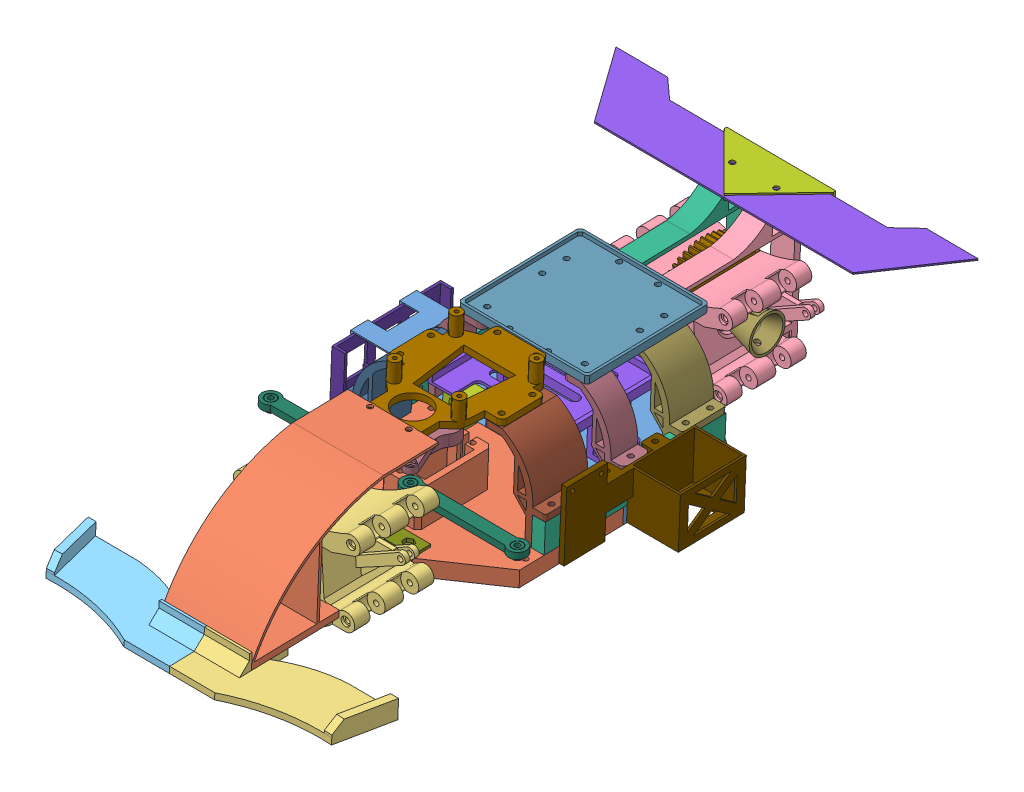
SolidWorks assembly Assem1, configuration Default. Lengths in mm.
Overall size (281.48 111.73 517.58).
43 component instances, 34 part files, 118 mates.
Components (placement in the parent):
- BB_Base-1: BB_Base [Default] at (28.6093 93.0226 121.9081) x (-0.998953 0.035235 0.029162) z (-0.029384 -0.005782 -0.999551) size (160 12.5 120)
- FF_Base-1: FF_Base [Default] at (31.1069 93.5141 206.87) x (0.998953 -0.035235 -0.029162) z (0.029384 0.005782 0.999551) size (160 41.5 120)
- FFDrive_BaseV2-1: FFDrive_BaseV2 [Default] at (33.3841 93.9622 284.3352) x (0.998953 -0.035235 -0.029162) z (0.029384 0.005782 0.999551) size (118.58 68.56 76.42)
- BBDrive_BaseV82-1: BBDrive_BaseV82 [Default] at (24.4221 92.1987 -20.528) x (0.998953 -0.035235 -0.029162) z (0.029384 0.005782 0.999551) size (118.58 68.56 102.04)
- SeizeF-1: SeizeF [Default] at (33.0586 90.9208 276.859) x (-0.998953 0.035235 0.029162) z (-0.029384 -0.005782 -0.999551) size (60 6.8 86)
- Body_sideL-1: Body_sideL [Default] at (-120.6554 114.7973 126.1701) x (-0.998953 0.035235 0.029162) z (0.03505 0.999362 -0.006811) size (10 148 23)
- Body_sideL-2: Body_sideL [Default] at (179.5564 119.2173 117.3192) x (0.998953 -0.035235 -0.029162) z (-0.03505 -0.999362 0.006811) size (10 148 23)
- Pi5_coverF-1: Pi5_coverF [Default] at (31.1961 123.3056 173.9303) x (0.998953 -0.035235 -0.029162) z (0.029384 0.005782 0.999551) size (85 35 25)
- Pi5_coverB-1: Pi5_coverB [Default] at (29.4104 122.9612 114.208) x (0.998953 -0.035235 -0.029162) z (0.029384 0.005782 0.999551) size (95 42 96)
- Lidar-1: Lidar [Default] at (34.5231 195.8195 208.2733) x (-0.029384 -0.005782 -0.999551) z (0.998953 -0.035235 -0.029162) size (114.37 20 89.02)
- LidarArmR-2: LidarArmR [Default] at (-15.6749 -85.014 186.3697) x (0.998559 -0.035298 -0.040412) z (0.040627 0.005385 0.99916) size (48.99 69.85 45)
- LidarArmL-2: LidarArmL [Default] at (64.8691 -87.5454 229.4349) x (-0.998953 0.035235 0.029162) z (-0.029384 -0.005782 -0.999551) size (48.99 69.85 45)
- LidarArmBack-1: LidarArmBack [Default] at (-18.294 -85.6212 83.8021) x (0.998953 -0.035235 -0.029162) z (0.029384 0.005782 0.999551) size (48.99 69.85 36)
- LidarArmBack-2: LidarArmBack [Default] at (61.5781 -88.193 117.4852) x (-0.998953 0.035235 0.029162) z (-0.029384 -0.005782 -0.999551) size (48.99 69.85 36)
- LidarArmMiddle-1: LidarArmMiddle [Default] at (-16.384 -85.2454 148.773) x (0.998953 -0.035235 -0.029162) z (0.029384 0.005782 0.999551) size (48.99 69.85 22)
- LidarArmMiddle-2: LidarArmMiddle [Default] at (62.9003 -87.9328 162.465) x (-0.998953 0.035235 0.029162) z (-0.029384 -0.005782 -0.999551) size (48.99 69.85 22)
- Box-1: Box [Default] at (-11.4334 176.0173 2.6909) x (0.998953 -0.035235 -0.029162) z (0.029384 0.005782 0.999551) size (100 6 100)
- MoterV3-1: MoterV3 [Default] at (-25.1001 106.1781 -59.4629) x (0.998953 -0.035235 -0.029162) z (0.03505 0.999362 -0.006811) size (37.37 43.05 44.5)
- FFBody_to_Drive-1: FFBody_to_Drive [Default] at (-13.9518 104.2128 3.1803) x (0.998953 -0.035235 -0.029162) z (0.029384 0.005782 0.999551) size (60 4 80)
- Battery-1: Battery [Default] at (74.6926 128.1789 305.2934) x (-0.998953 0.035235 0.029162) z (-0.029384 -0.005782 -0.999551) size (44 39 89)
- Radio-2: Radio [Default] at (-13.0755 129.1969 3.01) x (0.998953 -0.035235 -0.029162) z (0.029384 0.005782 0.999551) size (50 55 109.5)
- Battery_Lid-1: Battery_Lid [Default] at (-12.9003 134.1937 2.976) x (0.998953 -0.035235 -0.029162) z (0.029384 0.005782 0.999551) size (46 3 54)
- F1_1-1: F1_1 [Default] at (20.985 -17.6584 2.4568) x (0.998953 -0.035235 -0.029162) z (0.029384 0.005782 0.999551) size (70 82.35 150.07)
- F1_2-2: F1_2 [Default] at (64.4296 96.1923 0.5207) x (0.998953 -0.035235 -0.029162) z (0.029384 0.005782 0.999551) size (120 17.86 60)
- SpoilerTouch2-1: SpoilerTouch2 [Default] at (-4.7419 -16.7482 3.6059) x (0.998956 -0.035234 -0.029079) z (0.0293 0.005785 0.999554) size (18 100.35 111.06)
- F1_2_2-1: F1_2_2 [Default] at (64.4296 96.1923 0.5207) x (0.998953 -0.035235 -0.029162) z (0.029384 0.005782 0.999551) size (120 17.86 60)
- SpoilerTouch-5: SpoilerTouch [Default] at (-38.6157 -15.5519 4.8212) x (0.998773 -0.035267 -0.034779) z (0.034997 0.005584 0.999372) size (18 100.35 111.06)
- SpoilerCover-1: SpoilerCover [Default] at (-10.6832 197.6036 2.515) x (0.998969 -0.035232 -0.028621) z (0.028842 0.005801 0.999567) size (84.34 4.8 47)
- Spoiler-4: Spoiler [Default] at (-10.7673 195.2051 2.5313) x (0.998969 -0.035232 -0.028621) z (0.028842 0.005801 0.999567) size (140 1.2 60)
- Spoiler-5: Spoiler [Default] at (68.019 193.6272 0.2671) x (-0.998969 0.035232 0.028621) z (0.028842 0.005801 0.999567) size (140 1.2 60)
- GearRccar52T.step-1: GearRccar52T.step [Default] at (32.7657 128.7205 11.1737) x (-0.029157 0.000668 -0.999575) z (-0.998953 0.035235 0.029162) size (81 81 12.5)
  - Spur Gear (52 teeth).step-1: Spur Gear (52 teeth).step [Default] at origin size (81 81 12.5)
- Driven_axel-1: Driven_axel [Default] at (20.2788 129.161 11.5382) x (-0.035238 -0.999379 0.000398) z (0.029158 -0.00063 0.999575) size (17 42.75 17)
- GearRccar6T.step-1: GearRccar6T.step [Default] at (34.0925 129.4044 55.957) x (0.029157 -0.000668 0.999575) z (-0.998953 0.035235 0.029162) size (12 10.7 15.5)
  - Spur Gear (6 teeth).step-1: Spur Gear (6 teeth).step [Default] at origin size (12 10.7 15.5)
- CoverJoint_in-1: CoverJoint_in [Default] at (72.4741 127.3199 10.0145) x (0.035239 0.999379 -0.000387) z (0.029158 -0.000641 0.999575) size (29.5 27.5 29.5)
- CoverJoint_in-2: CoverJoint_in [Default] at (-19.6793 130.5704 12.7047) x (-0.035239 -0.999379 0.000387) z (0.029158 -0.000641 0.999575) size (29.5 27.5 29.5)
- Servohorn-1: Servohorn [Default] at (33.5475 145.3747 226.672) x (-0.008727 0 0.999962) z (0.008726 0.999962 0.000076) size (55.09 35.31 9)
- Gyro-1: Gyro [Default] at (-42.4215 108.8367 241.4574) x (0.998953 -0.035235 -0.029162) z (0.029384 0.005782 0.999551) size (22.2 9 18.5)
- ServoarmV85-1: ServoarmV85 [Default] at (-24.6411 140.7721 267.1832) x (-0.999924 0.008725 0.008729) z (0.008728 -0.000152 0.999962) size (99 8.2 14)
- ServoarmV85-2: ServoarmV85 [Default] at (90.927 137.5319 267.0158) x (0.999962 -0.008726 0.000049) z (0.00005 0.000076 -1) size (99 8.2 14)
- Supportbody-1: Supportbody [Default] at (89.3094 96.021 140.1153) x (-0.998953 0.035235 0.029162) z (0.029384 0.005782 0.999551) size (20 5 88)
- Supportbody-2: Supportbody [Default] at (-30.565 100.2492 143.6148) x (-0.998953 0.035235 0.029162) z (0.029384 0.005782 0.999551) size (20 5 88)
Mates (geometry in assembly coordinates):
- Coincident4: coincident anti-aligned: line of BB_Base-1 through (-49.6201 108.5792 166.6369) axis (0.998953 -0.035235 -0.029162); line of FF_Base-1 through (110.2125 102.9416 161.9709) axis (-0.998953 0.035235 0.029162)
- Coincident5: coincident anti-aligned: plane of BB_Base-1 through (110.2125 102.9416 161.9709) normal (0.029384 0.005782 0.999551); plane of FF_Base-1 through (-49.6201 108.5792 166.6369) normal (-0.029384 -0.005782 -0.999551)
- Coincident6: coincident aligned: line of BB_Base-1 through (110.2125 102.9416 161.9709) axis (-0.03505 -0.999362 0.006811); line of FF_Base-1 through (110.2125 102.9416 161.9709) axis (-0.03505 -0.999362 0.006811)
- Coincident10: coincident aligned: line of BB_Base-1 through (56.8816 95.6016 58.534) axis (-0.998953 0.035235 0.029162); line of BBDrive_BaseV82-1 through (56.8816 95.6016 58.534) axis (-0.998953 0.035235 0.029162)
- Coincident11: coincident aligned: line of BB_Base-1 through (56.8816 95.6016 58.534) axis (-0.03505 -0.999362 0.006811); line of BBDrive_BaseV82-1 through (56.8816 95.6016 58.534) axis (-0.03505 -0.999362 0.006811)
- Concentric3: concentric anti-aligned: cylinder of FF_Base-1 through (13.0376 90.4307 277.4504) axis (0.03505 0.999362 -0.006811) radius 2.1; cylinder of SeizeF-1 through (13.3179 98.4211 277.3959) axis (-0.03505 -0.999362 0.006811) radius 2.1
- Concentric4: concentric anti-aligned: cylinder of FF_Base-1 through (52.9958 89.0213 276.2839) axis (0.03505 0.999362 -0.006811) radius 2.1; cylinder of SeizeF-1 through (53.276 97.0117 276.2294) axis (-0.03505 -0.999362 0.006811) radius 2.1
- Coincident19: coincident anti-aligned: plane of FF_Base-1 through (31.1069 93.5141 206.87) normal (-0.03505 -0.999362 0.006811); plane of SeizeF-1 through (33.1638 93.9188 276.8386) normal (0.03505 0.999362 -0.006811)
- Concentric5: concentric anti-aligned: cylinder of FFDrive_BaseV2-1 through (34.3451 79.7606 334.4115) axis (0.03505 0.999362 -0.006811) radius 2.1; cylinder of SeizeF-1 through (34.9865 98.0489 334.2869) axis (-0.03505 -0.999362 0.006811) radius 2.1
- Concentric6: concentric anti-aligned: cylinder of FFDrive_BaseV2-1 through (33.3167 79.5582 299.4272) axis (0.03505 0.999362 -0.006811) radius 2.1; cylinder of SeizeF-1 through (33.9581 97.8465 299.3026) axis (-0.03505 -0.999362 0.006811) radius 2.1
- Coincident20: coincident anti-aligned: plane of FFDrive_BaseV2-1 through (35.2941 94.3381 349.3061) normal (-0.03505 -0.999362 0.006811); plane of SeizeF-1 through (33.1638 93.9188 276.8386) normal (0.03505 0.999362 -0.006811)
- Coincident21: coincident anti-aligned: plane of FF_Base-1 through (3.8537 107.5113 285.1249) normal (0.029384 0.005782 0.999551); plane of FFDrive_BaseV2-1 through (33.3841 93.9622 284.3352) normal (-0.029384 -0.005782 -0.999551)
- Concentric10: concentric aligned: cylinder of FF_Base-1 through (-12.3648 85.3832 184.9345) axis (0.03505 0.999362 -0.006811) radius 2.1; cylinder of Pi5_coverF-1 through (-12.4699 82.3851 184.9549) axis (0.03505 0.999362 -0.006811) radius 2.1
- Concentric11: concentric aligned: cylinder of FF_Base-1 through (-12.7762 85.3022 170.9408) axis (0.03505 0.999362 -0.006811) radius 2.1; cylinder of Pi5_coverF-1 through (-12.8813 82.3042 170.9612) axis (0.03505 0.999362 -0.006811) radius 2.1
- Coincident28: coincident anti-aligned: plane of FF_Base-1 through (31.545 106.0061 206.7848) normal (0.03505 0.999362 -0.006811); plane of Pi5_coverF-1 through (31.4642 105.9902 204.0361) normal (-0.03505 -0.999362 0.006811)
- Parallel3: parallel aligned: cylinder of BB_Base-1 through (-14.3146 69.127 138.8151) axis (0.03505 0.999362 -0.006811) radius 2.1; cylinder of Pi5_coverB-1 through (-13.1908 101.1669 138.5967) axis (0.03505 0.999362 -0.006811) radius 2.1
- Parallel4: parallel aligned: cylinder of BB_Base-1 through (-14.7847 69.0345 122.8223) axis (0.03505 0.999362 -0.006811) radius 2.1; cylinder of Pi5_coverB-1 through (-13.661 101.0744 122.6039) axis (0.03505 0.999362 -0.006811) radius 2.1
- Coincident29: coincident anti-aligned: plane of BB_Base-1 through (29.0474 105.5146 121.8229) normal (0.03505 0.999362 -0.006811); plane of Pi5_coverB-1 through (29.6786 105.6458 144.3137) normal (-0.03505 -0.999362 0.006811)
- Coincident30: coincident anti-aligned: plane of BB_Base-1 through (29.0474 105.5146 121.8229) normal (0.03505 0.999362 -0.006811); plane of Pi5_coverB-1 through (29.6786 105.6458 144.3137) normal (-0.03505 -0.999362 0.006811)
- Concentric16: concentric aligned: cylinder of BB_Base-1 through (-47.7404 81.9859 91.7018) axis (0.03505 0.999362 -0.006811) radius 2.1; cylinder of Body_sideL-1 through (-47.3899 91.9795 91.6337) axis (0.03505 0.999362 -0.006811) radius 2.1
- Concentric17: concentric aligned: cylinder of FF_Base-1 through (-43.9205 82.7376 221.6435) axis (0.03505 0.999362 -0.006811) radius 2.1; cylinder of Body_sideL-1 through (-43.57 92.7312 221.5754) axis (0.03505 0.999362 -0.006811) radius 2.1
- Coincident32: coincident anti-aligned: plane of FF_Base-1 through (31.545 106.0061 206.7848) normal (0.03505 0.999362 -0.006811); plane of Body_sideL-1 through (-120.7956 110.7999 126.1973) normal (-0.03505 -0.999362 0.006811)
- Concentric18: concentric anti-aligned: cylinder of BB_Base-1 through (102.1026 76.7007 87.3274) axis (0.03505 0.999362 -0.006811) radius 2.1; cylinder of Body_sideL-2 through (104.3809 141.6592 86.8847) axis (-0.03505 -0.999362 0.006811) radius 2.1
- Concentric19: concentric anti-aligned: cylinder of FF_Base-1 through (105.9225 77.4524 217.2691) axis (0.03505 0.999362 -0.006811) radius 2.1; cylinder of Body_sideL-2 through (108.2008 142.4109 216.8264) axis (-0.03505 -0.999362 0.006811) radius 2.1
- Coincident33: coincident anti-aligned: plane of FF_Base-1 through (31.545 106.0061 206.7848) normal (0.03505 0.999362 -0.006811); plane of Body_sideL-2 through (178.8904 100.2294 117.4486) normal (-0.03505 -0.999362 0.006811)
- Concentric33: concentric aligned: cylinder of BB_Base-1 through (-14.7847 69.0345 122.8223) axis (0.03505 0.999362 -0.006811) radius 2.1; cylinder of Pi5_coverB-1 through (-13.661 101.0744 122.6039) axis (0.03505 0.999362 -0.006811) radius 2.1
- Concentric34: concentric aligned: cylinder of BB_Base-1 through (-14.3146 69.127 138.8151) axis (0.03505 0.999362 -0.006811) radius 2.1; cylinder of Pi5_coverB-1 through (-13.1908 101.1669 138.5967) axis (0.03505 0.999362 -0.006811) radius 2.1
- Coincident40: coincident anti-aligned: plane of BB_Base-1 through (29.0474 105.5146 121.8229) normal (0.03505 0.999362 -0.006811); plane of Pi5_coverB-1 through (29.6786 105.6458 144.3137) normal (-0.03505 -0.999362 0.006811)
- Parallel10: parallel aligned: cylinder of BB_Base-1 through (70.1863 66.0374 120.3417) axis (0.03505 0.999362 -0.006811) radius 2.1; cylinder of Pi5_coverB-1 through (71.2501 98.0794 120.1251) axis (0.03505 0.999362 -0.006811) radius 2.1
- Parallel11: parallel aligned: cylinder of BB_Base-1 through (70.6564 66.13 136.3346) axis (0.03505 0.999362 -0.006811) radius 2.1; cylinder of Pi5_coverB-1 through (71.7202 98.1719 136.1179) axis (0.03505 0.999362 -0.006811) radius 2.1
- Coincident41: coincident anti-aligned: plane of BB_Base-1 through (29.0474 105.5146 121.8229) normal (0.03505 0.999362 -0.006811); plane of Pi5_coverB-1 through (29.6786 105.6458 144.3137) normal (-0.03505 -0.999362 0.006811)
- Concentric41: concentric aligned: cylinder of Body_sideL-1 through (-43.57 92.7312 221.5754) axis (0.03505 0.999362 -0.006811) radius 2.1; cylinder of LidarArmR-2 through (-43.6051 91.7319 221.5822) axis (0.03505 0.999362 -0.006811) radius 2.1
- Coincident46: coincident anti-aligned: plane of Body_sideL-1 through (-119.9895 133.7852 126.0407) normal (0.03505 0.999362 -0.006811); plane of LidarArmR-2 through (-6.2964 130.5053 229.8646) normal (-0.03505 -0.999362 0.006811)
- Concentric42: concentric aligned: cylinder of Lidar-1 through (-5.6367 177.1545 199.361) axis (0.03505 0.999362 -0.006811) radius 2.1; cylinder of LidarArmR-2 through (-7.214 132.1832 199.6675) axis (0.03505 0.999362 -0.006811) radius 2.1
- Parallel13: parallel aligned: cylinder of Lidar-1 through (-4.8964 177.3002 224.546) axis (0.03505 0.999362 -0.006811) radius 2.1; cylinder of LidarArmR-2 through (-6.1902 132.3189 224.8463) axis (0.03505 0.999362 -0.006811) radius 2.1
- Concentric44: concentric anti-aligned: cylinder of Body_sideL-2 through (108.2008 142.4109 216.8264) axis (-0.03505 -0.999362 0.006811) radius 2.1; cylinder of LidarArmL-2 through (106.238 86.4466 217.2078) axis (0.03505 0.999362 -0.006811) radius 2.1
- Concentric45: concentric anti-aligned: cylinder of Body_sideL-2 through (107.4662 142.2664 191.8376) axis (-0.03505 -0.999362 0.006811) radius 2.1; cylinder of LidarArmL-2 through (105.5034 86.3021 192.219) axis (0.03505 0.999362 -0.006811) radius 2.1
- Coincident48: coincident anti-aligned: plane of Body_sideL-2 through (179.6966 123.2147 117.2919) normal (0.03505 0.999362 -0.006811); plane of LidarArmL-2 through (71.0971 127.4714 182.9878) normal (-0.03505 -0.999362 0.006811)
- Parallel14: parallel aligned: cylinder of Lidar-1 through (73.4221 174.5378 222.2597) axis (0.03505 0.999362 -0.006811) radius 2.1; cylinder of LidarArmL-2 through (72.0928 129.5605 222.9644) axis (0.03505 0.999362 -0.006811) radius 2.1
- Parallel15: parallel anti-aligned: line of Lidar-1 through (78.7541 174.3565 223.1044) axis (-0.029384 -0.005782 -0.999551); line of LidarArmL-2 through (77.7992 174.1134 182.521) axis (0.029384 0.005782 0.999551)
- Concentric46: concentric aligned: cylinder of Body_sideL-1 through (-46.8022 92.0952 111.6247) axis (0.03505 0.999362 -0.006811) radius 2.1; cylinder of LidarArmBack-1 through (-45.5755 127.0729 111.3863) axis (0.03505 0.999362 -0.006811) radius 2.1
- Concentric47: concentric aligned: cylinder of Body_sideL-1 through (-47.3899 91.9795 91.6337) axis (0.03505 0.999362 -0.006811) radius 2.1; cylinder of LidarArmBack-1 through (-46.1631 126.9572 91.3953) axis (0.03505 0.999362 -0.006811) radius 2.1
- Coincident49: coincident anti-aligned: plane of Body_sideL-1 through (-119.9895 133.7852 126.0407) normal (0.03505 0.999362 -0.006811); plane of LidarArmBack-1 through (-9.4213 129.916 127.3147) normal (-0.03505 -0.999362 0.006811)
- Concentric48: concentric anti-aligned: cylinder of Body_sideL-2 through (104.9686 141.7749 106.8757) axis (-0.03505 -0.999362 0.006811) radius 2.1; cylinder of LidarArmBack-2 through (104.2676 121.7876 107.012) axis (0.03505 0.999362 -0.006811) radius 2.1
- Concentric49: concentric anti-aligned: cylinder of Body_sideL-2 through (104.3809 141.6592 86.8847) axis (-0.03505 -0.999362 0.006811) radius 2.1; cylinder of LidarArmBack-2 through (103.6799 121.672 87.0209) axis (0.03505 0.999362 -0.006811) radius 2.1
- Coincident50: coincident anti-aligned: plane of Body_sideL-2 through (179.6966 123.2147 117.2919) normal (0.03505 0.999362 -0.006811); plane of LidarArmBack-2 through (67.8061 126.8238 71.0381) normal (-0.03505 -0.999362 0.006811)
- Coincident51: coincident aligned: circle of Body_sideL-1; cylinder of LidarArmMiddle-1 through (-44.2532 127.3331 156.3661) axis (0.03505 0.999362 -0.006811) radius 2.1
- Coincident52: coincident aligned: line of Body_sideL-1 through (-46.904 131.9403 231.4511) axis (-0.029384 -0.005782 -0.999551); line of LidarArmMiddle-1 through (-48.9021 131.5472 163.4816) axis (-0.029384 -0.005782 -0.999551)
- Coincident53: coincident anti-aligned: line of Body_sideL-2 through (112.9286 126.3028 226.7851) axis (-0.029384 -0.005782 -0.999551); line of LidarArmMiddle-2 through (110.5191 125.8286 144.8218) axis (0.029384 0.005782 0.999551)
- Concentric50: concentric anti-aligned: cylinder of Body_sideL-2 through (106.2908 142.0351 151.8555) axis (-0.03505 -0.999362 0.006811) radius 2.1; cylinder of LidarArmMiddle-2 through (105.5898 122.0478 151.9918) axis (0.03505 0.999362 -0.006811) radius 2.1
- Coincident54: coincident anti-aligned: plane of LidarArmMiddle-2 through (70.7705 173.9045 115.6988) normal (0.03505 0.999362 -0.006811); plane of Box-1 through (-11.4334 176.0173 2.6909) normal (-0.03505 -0.999362 0.006811)
- Concentric51: concentric anti-aligned: cylinder of LidarArmBack-1 through (-7.4988 167.4689 90.0243) axis (0.03505 0.999362 -0.006811) radius 2.1; cylinder of Box-1 through (-7.0782 179.4612 89.9426) axis (-0.03505 -0.999362 0.006811) radius 2.1
- Concentric52: concentric anti-aligned: cylinder of LidarArmBack-1 through (-6.9111 167.5845 110.0154) axis (0.03505 0.999362 -0.006811) radius 2.1; cylinder of Box-1 through (-6.4905 179.5768 109.9336) axis (-0.03505 -0.999362 0.006811) radius 2.1
- Concentric53: concentric anti-aligned: cylinder of LidarArmMiddle-1 through (-5.5889 167.8447 154.9952) axis (0.03505 0.999362 -0.006811) radius 2.1; cylinder of Box-1 through (-5.1683 179.837 154.9134) axis (-0.03505 -0.999362 0.006811) radius 2.1
- Parallel16: parallel anti-aligned: cylinder of LidarArmMiddle-2 through (69.8593 165.1835 152.7926) axis (0.03505 0.999362 -0.006811) radius 2.1; cylinder of Box-1 through (70.2714 177.1762 152.7111) axis (-0.03505 -0.999362 0.006811) radius 2.1
- Concentric55: concentric anti-aligned: cylinder of BB_Base-1 through (-33.6175 69.3783 76.3528) axis (0.03505 0.999362 -0.006811) radius 2.1; cylinder of MoterV3-1 through (-32.1278 111.8512 76.0634) axis (-0.03505 -0.999362 0.006811) radius 2.1
- Concentric56: concentric anti-aligned: cylinder of BB_Base-1 through (-8.6436 68.4974 75.6238) axis (0.03505 0.999362 -0.006811) radius 2.1; cylinder of MoterV3-1 through (-7.154 110.9703 75.3343) axis (-0.03505 -0.999362 0.006811) radius 2.1
- Coincident55: coincident anti-aligned: plane of BB_Base-1 through (29.0474 105.5146 121.8229) normal (0.03505 0.999362 -0.006811); plane of MoterV3-1 through (-25.1001 106.1781 -59.4629) normal (-0.03505 -0.999362 0.006811)
- Coincident57: coincident anti-aligned: plane of FFDrive_BaseV2-1 through (35.6621 104.8314 349.2345) normal (0.03505 0.999362 -0.006811); plane of FFBody_to_Drive-1 through (-13.9518 104.2128 3.1803) normal (-0.03505 -0.999362 0.006811)
- Concentric57: concentric anti-aligned: cylinder of FFDrive_BaseV2-1 through (34.3451 79.7606 334.4115) axis (0.03505 0.999362 -0.006811) radius 2.1; cylinder of FFBody_to_Drive-1 through (35.3616 108.7421 334.214) axis (-0.03505 -0.999362 0.006811) radius 2.1
- Concentric58: concentric anti-aligned: cylinder of FF_Base-1 through (13.0376 90.4307 277.4504) axis (0.03505 0.999362 -0.006811) radius 2.1; cylinder of FFBody_to_Drive-1 through (13.6929 109.1143 277.3231) axis (-0.03505 -0.999362 0.006811) radius 2.1
- Concentric59: concentric anti-aligned: cylinder of FF_Base-1 through (52.9958 89.0213 276.2839) axis (0.03505 0.999362 -0.006811) radius 2.1; cylinder of FFBody_to_Drive-1 through (53.6511 107.7049 276.1566) axis (-0.03505 -0.999362 0.006811) radius 2.1
- Coincident60: coincident anti-aligned: plane of Body_sideL-1 through (-119.9895 133.7852 126.0407) normal (0.03505 0.999362 -0.006811); plane of Battery-1 through (74.6926 128.1789 305.2934) normal (-0.03505 -0.999362 0.006811)
- Concentric64: concentric anti-aligned: cylinder of Body_sideL-1 through (-46.0676 92.2397 136.6135) axis (0.03505 0.999362 -0.006811) radius 2.1; cylinder of Battery-1 through (-44.5254 136.2117 136.3138) axis (-0.03505 -0.999362 0.006811) radius 2.1
- Concentric65: concentric anti-aligned: cylinder of Body_sideL-1 through (-44.8923 92.471 176.5956) axis (0.03505 0.999362 -0.006811) radius 2.1; cylinder of Battery-1 through (-43.3501 136.443 176.2959) axis (-0.03505 -0.999362 0.006811) radius 2.1
- Coincident61: coincident anti-aligned: plane of Body_sideL-2 through (179.6966 123.2147 117.2919) normal (0.03505 0.999362 -0.006811); plane of Radio-2 through (-13.0755 129.1969 3.01) normal (-0.03505 -0.999362 0.006811)
- Concentric66: concentric aligned: cylinder of Body_sideL-2 through (105.7032 141.9194 131.8645) axis (-0.03505 -0.999362 0.006811) radius 2.1; cylinder of Radio-2 through (105.3176 130.9265 131.9394) axis (-0.03505 -0.999362 0.006811) radius 2.1
- Concentric67: concentric aligned: cylinder of Body_sideL-2 through (106.8785 142.1507 171.8466) axis (-0.03505 -0.999362 0.006811) radius 2.1; cylinder of Radio-2 through (106.493 131.1577 171.9215) axis (-0.03505 -0.999362 0.006811) radius 2.1
- Coincident62: coincident anti-aligned: plane of Battery-1 through (74.8678 133.1757 305.2593) normal (0.03505 0.999362 -0.006811); plane of Battery_Lid-1 through (-12.9003 134.1937 2.976) normal (-0.03505 -0.999362 0.006811)
- Concentric68: concentric aligned: cylinder of Battery-1 through (-43.3501 136.443 176.2959) axis (-0.03505 -0.999362 0.006811) radius 2.1; cylinder of Battery_Lid-1 through (-43.315 137.4423 176.2891) axis (-0.03505 -0.999362 0.006811) radius 2.1
- Concentric69: concentric anti-aligned: cylinder of Body_sideL-1 through (-46.0676 92.2397 136.6135) axis (0.03505 0.999362 -0.006811) radius 2.1; cylinder of Battery_Lid-1 through (-44.4904 137.211 136.307) axis (-0.03505 -0.999362 0.006811) radius 2.1
- Coincident69: coincident anti-aligned: plane of Lidar-1 through (33.9974 180.8291 208.3755) normal (0.03505 0.999362 -0.006811); plane of F1_1-1 through (-7.0589 180.8633 2.1328) normal (-0.03505 -0.999362 0.006811)
- Concentric79: concentric aligned: cylinder of Lidar-1 through (20.7606 176.7391 274.2534) axis (0.03505 0.999362 -0.006811) radius 2.1; cylinder of F1_1-1 through (19.7792 148.757 274.4441) axis (0.03505 0.999362 -0.006811) radius 2.1
- Concentric80: concentric aligned: cylinder of Lidar-1 through (50.7292 175.6821 273.3785) axis (0.03505 0.999362 -0.006811) radius 2.1; cylinder of F1_1-1 through (49.7478 147.6999 273.5692) axis (0.03505 0.999362 -0.006811) radius 2.1
- Parallel17: parallel aligned: cylinder of FFDrive_BaseV2-1 through (55.3149 90.6642 353.741) axis (0.03505 0.999362 -0.006811) radius 2.1; cylinder of F1_1-1 through (54.3694 70.6828 353.4829) axis (0.03505 0.999362 -0.006811) radius 2.1
- Parallel18: parallel aligned: cylinder of FFDrive_BaseV2-1 through (15.3568 92.0736 354.9075) axis (0.03505 0.999362 -0.006811) radius 2.1; cylinder of F1_1-1 through (14.4113 72.0922 354.6494) axis (0.03505 0.999362 -0.006811) radius 2.1
- Concentric81: concentric aligned: cylinder of F1_1-1 through (47.4851 116.3071 405.4447) axis (-0.03505 -0.999362 0.006811) radius 2.1; cylinder of F1_2-2 through (46.9593 101.3167 405.5468) axis (-0.03505 -0.999362 0.006811) radius 2.1
- Coincident71: coincident anti-aligned: plane of F1_1-1 through (-9.8753 100.5642 2.6801) normal (-0.03505 -0.999362 0.006811); plane of F1_2-2 through (0.9195 102.7892 384.6716) normal (0.03505 0.999362 -0.006811)
- Concentric83: concentric anti-aligned: cylinder of Box-1 through (45.0695 177.4927 69.4769) axis (-0.03505 -0.999362 0.006811) radius 2.1; cylinder of SpoilerTouch2-1 through (42.5809 106.538 69.9605) axis (0.03505 0.999362 -0.006811) radius 2.1
- Parallel20: parallel: cylinder of BBDrive_BaseV82-1 through (44.1478 90.4682 -26.1001) axis (0.03505 0.999362 -0.006811) radius 2.1; cylinder of SpoilerTouch2-1 through (42.2952 35.5006 -25.7273) axis (0.03505 0.999362 -0.006811) radius 2.1
- Coincident74: coincident anti-aligned: plane of Box-1 through (-11.4334 176.0173 2.6909) normal (-0.03505 -0.999362 0.006811); plane of SpoilerTouch2-1 through (53.948 173.7112 0.7832) normal (0.03505 0.999362 -0.006811)
- Coincident75: coincident anti-aligned: plane of Lidar-1 through (33.8221 175.8322 208.4096) normal (-0.03505 -0.999362 0.006811); plane of LidarArmR-2 through (-4.6542 177.3258 229.5455) normal (0.03505 0.999362 -0.006811)
- Coincident76: coincident anti-aligned: plane of FFDrive_BaseV2-1 through (5.8647 102.4485 360.1288) normal (0.03505 0.999362 -0.006811); plane of F1_1-1 through (-9.8753 100.5642 2.6801) normal (-0.03505 -0.999362 0.006811)
- Parallel21: parallel aligned: cylinder of Lidar-1 through (72.6817 174.3921 197.0746) axis (0.03505 0.999362 -0.006811) radius 2.1; cylinder of LidarArmL-2 through (71.3523 129.4148 197.7757) axis (0.03505 0.999362 -0.006811) radius 2.1
- Concentric86: concentric aligned: cylinder of Lidar-1 through (-5.6367 177.1545 199.361) axis (0.03505 0.999362 -0.006811) radius 2.1; cylinder of LidarArmR-2 through (-7.214 132.1832 199.6675) axis (0.03505 0.999362 -0.006811) radius 2.1
- Concentric90: concentric aligned: cylinder of F1_1-1 through (12.5217 117.5404 406.4653) axis (-0.03505 -0.999362 0.006811) radius 2.1; cylinder of F1_2_2-1 through (11.996 102.5499 406.5675) axis (-0.03505 -0.999362 0.006811) radius 2.1
- Coincident81: coincident anti-aligned: circle of F1_1-1; cylinder of F1_2_2-1 through (26.9803 102.0214 406.1301) axis (-0.03505 -0.999362 0.006811) radius 2.1
- Coincident82: coincident anti-aligned: plane of F1_1-1 through (-9.8753 100.5642 2.6801) normal (-0.03505 -0.999362 0.006811); plane of F1_2_2-1 through (0.9195 102.7892 384.6716) normal (0.03505 0.999362 -0.006811)
- Concentric92: concentric: cylinder of BBDrive_BaseV82-1 through (4.2113 91.8808 -24.3454) axis (0.03505 0.999362 -0.006811) radius 2.1; cylinder of SpoilerTouch-5 through (4.3164 94.8789 -24.3659) axis (0.03505 0.999362 -0.006811) radius 2.1
- Coincident90: coincident anti-aligned: plane of BBDrive_BaseV82-1 through (32.3652 98.8545 -30.8045) normal (0.03505 0.999362 -0.006811); plane of SpoilerTouch-5 through (17.4236 99.6036 2.2153) normal (-0.03505 -0.999362 0.006811)
- Coincident92: coincident anti-aligned: plane of Box-1 through (-11.4334 176.0173 2.6909) normal (-0.03505 -0.999362 0.006811); plane of SpoilerTouch-5 through (20.0647 174.9059 1.7021) normal (0.03505 0.999362 -0.006811)
- Coincident95: coincident anti-aligned: circle of SpoilerTouch-5; circle of SpoilerCover-1
- Concentric93: concentric aligned: cylinder of SpoilerTouch2-1 through (44.4515 180.8756 -24.631) axis (0.03505 0.999362 -0.006811) radius 2.1; cylinder of SpoilerCover-1 through (44.8371 191.8685 -24.7059) axis (0.03505 0.999362 -0.006811) radius 2.1
- Concentric94: concentric aligned: cylinder of SpoilerCover-1 through (10.9776 197.8656 -23.7637) axis (-0.03505 -0.999362 0.006811) radius 2.1; cylinder of Spoiler-4 through (10.8935 195.4671 -23.7473) axis (-0.03505 -0.999362 0.006811) radius 2.1
- Coincident100: coincident anti-aligned: plane of SpoilerCover-1 through (-10.7673 195.2051 2.5313) normal (0.03505 0.999362 -0.006811); plane of Spoiler-5 through (67.9769 192.428 0.2753) normal (-0.03505 -0.999362 0.006811)
- Coincident101: coincident anti-aligned: circle of SpoilerCover-1; cylinder of Spoiler-5 through (44.8791 193.0678 -24.7141) axis (0.03505 0.999362 -0.006811) radius 2.1
- Coincident102: coincident anti-aligned: plane of SpoilerCover-1 through (-14.8378 195.0375 -43.0103) normal (0.028842 0.005801 0.999567); plane of Spoiler-5 through (32.6692 346.9694 -45.2629) normal (-0.028842 -0.005801 -0.999567)
- Coincident103: coincident anti-aligned: plane of SpoilerCover-1 through (-14.8378 195.0375 -43.0103) normal (0.028842 0.005801 0.999567); plane of Spoiler-4 through (21.9497 41.3335 -43.1798) normal (-0.028842 -0.005801 -0.999567)
- Coincident104: coincident anti-aligned: plane of SpoilerCover-1 through (-10.7673 195.2051 2.5313) normal (0.03505 0.999362 -0.006811); plane of Spoiler-4 through (-10.7673 195.2051 2.5313) normal (-0.03505 -0.999362 0.006811)
- Coincident107: coincident anti-aligned: plane of GearRccar52T.step-1/Spur Gear (52 teeth).step-1 through (20.2788 129.161 11.5382) normal (-0.998953 0.035235 0.029162); plane of Driven_axel-1 through (20.2788 129.161 11.5382) normal (0.998953 -0.035235 -0.029162)
- Concentric95: concentric aligned: cylinder of GearRccar52T.step-1/Spur Gear (52 teeth).step-1 through (32.7657 128.7205 11.1737) axis (-0.998953 0.035235 0.029162) radius 7.5; cylinder of Driven_axel-1 through (66.4436 127.5327 10.1905) axis (-0.998953 0.035235 0.029162) radius 7.5
- Coincident108: coincident anti-aligned: circle of GearRccar52T.step-1/Spur Gear (52 teeth).step-1; cylinder of Driven_axel-1 through (66.4436 127.5327 10.1905) axis (-0.998953 0.035235 0.029162) radius 7.5
- Concentric97: concentric aligned: cylinder of MoterV3-1 through (-25.9635 131.5227 57.7102) axis (0.998953 -0.035235 -0.029162) radius 2.5; cylinder of GearRccar6T.step-1/Spur Gear (6 teeth).step-1 through (18.6088 129.9505 56.409) axis (0.998953 -0.035235 -0.029162) radius 1.6435
- Concentric98: concentric aligned: cylinder of Driven_axel-1 through (47.75 128.192 10.7362) axis (-0.998953 0.035235 0.029162) radius 2.5; circle of CoverJoint_in-1
- Concentric99: concentric anti-aligned: cylinder of Driven_axel-1 through (47.75 128.192 10.7362) axis (-0.998953 0.035235 0.029162) radius 2.5; cylinder of CoverJoint_in-2 through (-29.9186 130.9315 13.0036) axis (0.998953 -0.035235 -0.029162) radius 2.1
- Coincident109: coincident anti-aligned: plane of Driven_axel-1 through (5.0448 129.6983 11.9829) normal (-0.998953 0.035235 0.029162); plane of CoverJoint_in-2 through (5.0448 129.6983 11.9829) normal (0.998953 -0.035235 -0.029162)
- Coincident110: coincident anti-aligned: plane of Driven_axel-1 through (47.8228 130.2574 10.7354) normal (0.998953 -0.035235 -0.029162); plane of CoverJoint_in-1 through (47.75 128.192 10.7362) normal (-0.998953 0.035235 0.029162)
- Concentric100: concentric anti-aligned: cylinder of FF_Base-1 through (-43.3328 82.8532 241.6345) axis (0.03505 0.999362 -0.006811) radius 2.1; cylinder of Gyro-1 through (-42.3514 110.8354 241.4438) axis (-0.03505 -0.999362 0.006811) radius 2.1
- Coincident111: coincident anti-aligned: plane of FF_Base-1 through (31.545 106.0061 206.7848) normal (0.03505 0.999362 -0.006811); plane of Gyro-1 through (-42.4215 108.8367 241.4574) normal (-0.03505 -0.999362 0.006811)
- Coincident112: coincident anti-aligned: line of FF_Base-1 through (-49.6201 108.5792 166.6369) axis (0.029384 0.005782 0.999551); line of Gyro-1 through (-47.2106 109.0533 248.6001) axis (-0.029384 -0.005782 -0.999551)
- Concentric101: concentric anti-aligned: cylinder of Servohorn-1 through (20.4349 149.4862 266.7911) axis (0.008726 0.999962 0.000076) radius 2.1427; cylinder of ServoarmV85-1 through (20.4017 145.6792 266.7908) axis (-0.008726 -0.999962 -0.000076) radius 2.1
- Concentric102: concentric anti-aligned: cylinder of Servohorn-1 through (46.0277 149.2629 267.0145) axis (0.008726 0.999962 0.000076) radius 2.1427; cylinder of ServoarmV85-2 through (45.975 143.2244 267.014) axis (-0.008726 -0.999962 -0.000076) radius 2.1
- Concentric103: concentric anti-aligned: cylinder of FF_Base-1 through (91.7644 117.3458 198.446) axis (-0.03505 -0.999362 0.006811) radius 2.1; cylinder of Supportbody-1 through (90.8531 91.3624 198.6231) axis (0.03505 0.999362 -0.006811) radius 2.1
- Concentric104: concentric anti-aligned: cylinder of BB_Base-1 through (89.6488 116.9295 126.4783) axis (-0.03505 -0.999362 0.006811) radius 2.1; cylinder of Supportbody-1 through (88.7375 90.9461 126.6554) axis (0.03505 0.999362 -0.006811) radius 2.1
- Coincident113: coincident anti-aligned: plane of BB_Base-1 through (28.7845 98.0194 121.874) normal (-0.03505 -0.999362 0.006811); plane of Supportbody-1 through (89.3094 96.021 140.1153) normal (0.03505 0.999362 -0.006811)
- Concentric105: concentric anti-aligned: cylinder of FF_Base-1 through (-28.11 121.574 201.9455) axis (-0.03505 -0.999362 0.006811) radius 2.1; cylinder of Supportbody-2 through (-29.0213 95.5906 202.1226) axis (0.03505 0.999362 -0.006811) radius 2.1
- Concentric106: concentric anti-aligned: cylinder of BB_Base-1 through (-30.2256 121.1577 129.9778) axis (-0.03505 -0.999362 0.006811) radius 2.1; cylinder of Supportbody-2 through (-31.137 95.1743 130.1549) axis (0.03505 0.999362 -0.006811) radius 2.1
- Coincident114: coincident anti-aligned: plane of BB_Base-1 through (28.7845 98.0194 121.874) normal (-0.03505 -0.999362 0.006811); plane of Supportbody-2 through (-30.565 100.2492 143.6148) normal (0.03505 0.999362 -0.006811)
